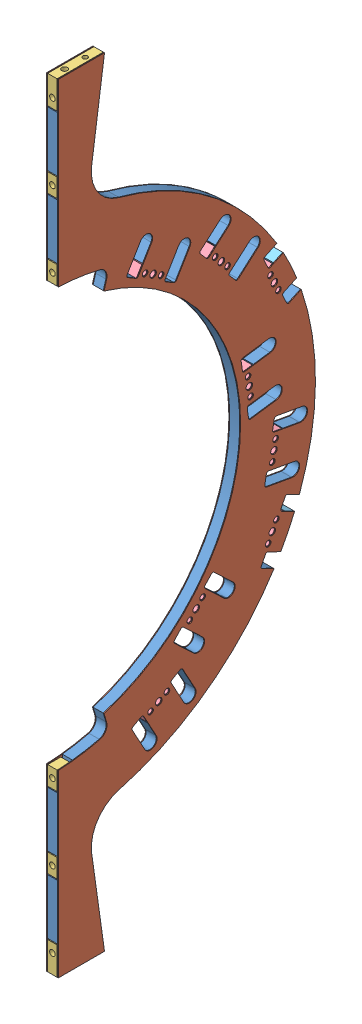
SolidWorks assembly Barrel 3 support panel assy, configuration Right. Lengths in mm.
Overall size (6.75 416 137.5).
28 component instances, 6 part files, 45 mates.
Components (placement in the parent):
- Barrel 3 support core-1: Barrel 3 support core [right] x (0 0 -1) z (1 0 0)
- Barrel 3 support skin-1: Barrel 3 support skin [barrel 3 right skin 1] at (2.92 0 0) x (0 0 -1) z (1 0 0) size (137.5 416 0.41)
- Barrel 3 support skin-2: Barrel 3 support skin [barrel 3 right skin 2] at (-2.92 0 0) x (0 0 -1) z (1 0 0)
- Barrel 1 support inserts-1: Barrel 1 support inserts [insert 1] x (0 0 -1) z (1 0 0) size (24.73 15 5.03)
- Barrel 1 support inserts-2: Barrel 1 support inserts [insert 1] x (0 0 -1) z (-1 0 0) size (24.73 15 5.03)
- Barrel 1 support inserts-3: Barrel 1 support inserts [insert 2] at (0 -3.5 0) x (0 0 -1) z (1 0 0) size (7.5 10 5.03)
- Barrel 1 support inserts-4: Barrel 1 support inserts [insert 2] at (0 44 0) x (0 0 -1) z (-1 0 0) size (7.5 10 5.03)
- Barrel 1 support inserts-5: Barrel 1 support inserts [insert 2] at (0 -44 0) x (0 0 -1) z (1 0 0) size (7.5 10 5.03)
- Barrel 1 support inserts-6: Barrel 1 support inserts [insert 2] at (0 3.5 0) x (0 0 -1) z (-1 0 0) size (7.5 10 5.03)
- Adhesive-1: Adhesive [Default] at origin
- Barrel 3-4 support panel ladder mounting block-1: Barrel 3-4 support panel ladder mounting block [Default for barrel 4 support panel] at (-0.505 92.4422 -55.2185) x (0 -0.858503 0.512809) z (0 0.512809 0.858503)
- Barrel 3-4 support panel ladder mounting block-18: Barrel 3-4 support panel ladder mounting block [Default for barrel 4 support panel] at (-0.505 80.0329 -91.7246) x (0 -0.657452 0.753497) z (0 0.753497 0.657452)
- Barrel 3-4 support panel ladder mounting block-24: Barrel 3-4 support panel ladder mounting block [Default for barrel 4 support panel] at (-0.505 56.1248 -120.0908) x (0 -0.423396 0.905945) z (0 0.905945 0.423396)
- Barrel 3-4 support panel ladder mounting block-19: Barrel 3-4 support panel ladder mounting block [Default for barrel 4 support panel] at (-0.505 -21.4676 -119.8241) x (0 0.176352 0.984327) z (0 0.984327 -0.176352)
- Barrel 3-4 support panel ladder mounting block-20: Barrel 3-4 support panel ladder mounting block [Default for barrel 4 support panel] at (-0.505 -106.8994 -58.2339) x (0 0.878154 0.478378) z (0 0.478378 -0.878154)
- Barrel 3-4 support panel ladder mounting block-13: Barrel 3-4 support panel ladder mounting block [Default for barrel 4 support panel] at (-0.505 14.7732 -106.6602) x (0 -0.137198 0.990544) z (0 0.990544 0.137198)
- Barrel 3-4 support panel ladder mounting block-14: Barrel 3-4 support panel ladder mounting block [Default for barrel 4 support panel] at (-0.505 -73.9537 -78.2656) x (0 0.686801 0.726845) z (0 0.726845 -0.686801)
- Barrel 3-4 support panel ladder mounting block-25: Barrel 3-4 support panel ladder mounting block [Default for barrel 4 support panel] at (-0.505 -58.5544 -118.925) x (0 0.441725 0.897151) z (0 0.897151 -0.441725)
- Barrel 3-4 support panel ladder mounting block-28: Barrel 3-4 support panel ladder mounting block [Default for barrel 4 support panel] at (0.505 92.4422 -55.2185) x (0 0.858503 -0.512809) z (0 0.512809 0.858503) (suppressed, hidden)
- Barrel 3-4 support panel ladder mounting block-34: Barrel 3-4 support panel ladder mounting block [Default for barrel 4 support panel] at (0.505 80.0329 -91.7246) x (0 0.657452 -0.753497) z (0 0.753497 0.657452) (suppressed, hidden)
- Barrel 3-4 support panel ladder mounting block-40: Barrel 3-4 support panel ladder mounting block [Default for barrel 4 support panel] at (0.505 56.1248 -120.0908) x (0 0.423396 -0.905945) z (0 0.905945 0.423396) (suppressed, hidden)
- Barrel 3-4 support panel ladder mounting block-35: Barrel 3-4 support panel ladder mounting block [Default for barrel 4 support panel] at (0.505 -21.4676 -119.8241) x (0 -0.176352 -0.984327) z (0 0.984327 -0.176352) (suppressed, hidden)
- Barrel 3-4 support panel ladder mounting block-36: Barrel 3-4 support panel ladder mounting block [Default for barrel 4 support panel] at (0.505 -106.8994 -58.2339) x (0 -0.878154 -0.478378) z (0 0.478378 -0.878154) (suppressed, hidden)
- Barrel 3-4 support panel ladder mounting block-29: Barrel 3-4 support panel ladder mounting block [Default for barrel 4 support panel] at (0.505 14.7732 -106.6602) x (0 0.137198 -0.990544) z (0 0.990544 0.137198) (suppressed, hidden)
- Barrel 3-4 support panel ladder mounting block-30: Barrel 3-4 support panel ladder mounting block [Default for barrel 4 support panel] at (0.505 -73.9537 -78.2656) x (0 -0.686801 -0.726845) z (0 0.726845 -0.686801) (suppressed, hidden)
- Barrel 3-4 support panel ladder mounting block-41: Barrel 3-4 support panel ladder mounting block [Default for barrel 4 support panel] at (0.505 -58.5544 -118.925) x (0 -0.441725 -0.897151) z (0 0.897151 -0.441725) (suppressed, hidden)
- Barrel 3 support core plug 1-1: Barrel 3 support core plug 1 [right] x (0 0.423396 -0.905945) z (1 0 0)
- Barrel 3 support core plug 1-2: Barrel 3 support core plug 1 [right] x (0 -0.441725 -0.897151) z (1 0 0)
Mates (geometry in assembly coordinates):
- Coincident1: coincident anti-aligned: plane of Barrel 3 support core-1 through (0 0 0) normal (0 0 -1); plane of assembly through (0 0 0) normal (0 0 1)
- Coincident2: coincident aligned: plane of Barrel 3 support core-1 through (0 0 0) normal (1 0 0); plane of assembly through (0 0 0) normal (1 0 0)
- Coincident3: coincident aligned: plane of Barrel 3 support core-1; plane of assembly through (0 0 0) normal (0 1 0)
- Coincident4: coincident aligned: plane of Barrel 1 support inserts-1 through (0 0 0) normal (1 0 0); plane of assembly through (0 0 0) normal (1 0 0)
- Coincident5: coincident anti-aligned: plane of Barrel 1 support inserts-1 through (0 0 0) normal (0 0 -1); plane of assembly through (0 0 0) normal (0 0 1)
- Coincident6: coincident aligned: plane of Barrel 1 support inserts-1; plane of assembly through (0 0 0) normal (0 1 0)
- Coincident7: coincident anti-aligned: plane of Barrel 1 support inserts-2; plane of assembly through (0 0 0) normal (0 1 0)
- Coincident8: coincident anti-aligned: plane of Barrel 1 support inserts-2; plane of assembly through (0 0 0) normal (0 0 1)
- Coincident9: coincident anti-aligned: plane of Barrel 1 support inserts-2 through (0 0 0) normal (-1 0 0); plane of assembly through (0 0 0) normal (1 0 0)
- Coincident10: coincident aligned: plane of Barrel 1 support inserts-3 through (0 -3.5 0) normal (1 0 0); plane of assembly through (0 0 0) normal (1 0 0)
- Coincident11: coincident anti-aligned: plane of Barrel 1 support inserts-3 through (0 -3.5 0) normal (0 0 -1); plane of assembly through (0 0 0) normal (0 0 1)
- Coincident13: coincident anti-aligned: plane of Barrel 1 support inserts-4 through (0 44 0) normal (-1 0 0); plane of assembly through (0 0 0) normal (1 0 0)
- Coincident14: coincident anti-aligned: plane of Barrel 1 support inserts-4; plane of assembly through (0 0 0) normal (0 0 1)
- Coincident18: coincident anti-aligned: plane of Barrel 3 support skin-1 through (2.92 0 0) normal (0 0 -1); plane of assembly through (0 0 0) normal (0 0 1)
- Coincident19: coincident aligned: plane of Barrel 3 support skin-1; plane of assembly through (0 0 0) normal (0 1 0)
- Coincident20: coincident aligned: plane of Barrel 3 support skin-2; plane of assembly through (0 0 0) normal (0 1 0)
- Coincident21: coincident anti-aligned: plane of Barrel 3 support skin-2 through (-2.92 0 0) normal (0 0 -1); plane of assembly through (0 0 0) normal (0 0 1)
- Coincident22: coincident anti-aligned: plane of Barrel 3 support core-1 through (2.715 156.4127 -42.1789) normal (1 0 0); plane of Barrel 3 support skin-1 through (2.715 156.4127 -42.1789) normal (-1 0 0)
- Coincident23: coincident anti-aligned: plane of Barrel 3 support core-1 through (-2.715 156.4127 -42.1789) normal (-1 0 0); plane of Barrel 3 support skin-2 through (-2.715 156.4127 -42.1789) normal (1 0 0)
- Distance1: distance = 3.5 mm aligned: plane of Barrel 1 support inserts-3; plane of assembly through (0 0 0) normal (0 1 0)
- Distance2: distance = 44 mm anti-aligned: plane of Barrel 1 support inserts-4; plane of assembly through (0 0 0) normal (0 1 0)
- Distance25: distance = 0.1 mm anti-aligned: plane of Barrel 3-4 support panel ladder mounting block-1 through (2.615 97.7849 -50.2561) normal (1 0 0); plane of Barrel 3 support skin-1 through (2.715 156.4127 -42.1789) normal (-1 0 0)
- Distance26: distance = 0.1 mm anti-aligned: plane of Barrel 3-4 support panel ladder mounting block-18 through (2.615 86.6499 -88.6611) normal (1 0 0); plane of Barrel 3 support skin-1 through (2.715 156.4127 -42.1789) normal (-1 0 0)
- Distance27: distance = 0.1 mm anti-aligned: plane of Barrel 3-4 support panel ladder mounting block-24 through (2.615 63.331 -118.9769) normal (1 0 0); plane of Barrel 3 support skin-1 through (2.715 156.4127 -42.1789) normal (-1 0 0)
- Distance3: distance = 0.25 mm anti-aligned: plane of Barrel 3-4 support panel ladder mounting block-1 through (-3.625 97.7849 -50.2561) normal (0 0.858503 -0.512809); plane of Barrel 3 support skin-2 through (-3.125 90.9484 -62.1887) normal (0 -0.858503 0.512809)
- Distance5: distance = 0.25 mm anti-aligned: plane of Barrel 3-4 support panel ladder mounting block-18 through (-3.625 86.6499 -88.6611) normal (0 0.657452 -0.753497); plane of Barrel 3 support skin-2 through (-3.125 86.6259 -89.0138) normal (0 -0.657452 0.753497)
- Distance7: distance = 0.25 mm anti-aligned: plane of Barrel 3-4 support panel ladder mounting block-24 through (-3.625 63.331 -118.9769) normal (0 0.423396 -0.905945); plane of Barrel 3 support skin-2 through (-3.125 63.2103 -119.3093) normal (0 -0.423396 0.905945)
- Distance10: distance = 0.25 mm anti-aligned: plane of Barrel 3-4 support panel ladder mounting block-24 through (-3.625 61.6018 -115.2771) normal (0 0.905945 0.423396); plane of Barrel 3 support skin-2 through (-3.125 63.4516 -118.6446) normal (0 -0.905945 -0.423396)
- Distance12: distance = 0.25 mm anti-aligned: plane of Barrel 3-4 support panel ladder mounting block-18 through (-3.625 83.9648 -85.5838) normal (0 0.753497 0.657452); plane of Barrel 3 support skin-2 through (-3.125 84.3176 -85.6078) normal (0 -0.753497 -0.657452)
- Distance14: distance = 0.25 mm anti-aligned: plane of Barrel 3-4 support panel ladder mounting block-1 through (-3.625 94.2788 -48.1618) normal (0 0.512809 0.858503); plane of Barrel 3 support skin-2 through (-3.125 94.6216 -48.0754) normal (0 -0.512809 -0.858503)
- Distance30: distance = 0.1 mm anti-aligned: plane of Barrel 3-4 support panel ladder mounting block-28 through (-3.225 85.486 -62.306) normal (1 0 0); plane of Barrel 3 support skin-2 through (-2.715 156.4127 -42.1789) normal (1 0 0)
- Distance29: distance = 0.1 mm anti-aligned: plane of Barrel 3-4 support panel ladder mounting block-34 through (-3.225 70.3366 -94.5466) normal (1 0 0); plane of Barrel 3 support skin-2 through (-2.715 156.4127 -42.1789) normal (1 0 0)
- Distance28: distance = 0.1 mm anti-aligned: plane of Barrel 3-4 support panel ladder mounting block-40 through (-3.225 46.7747 -121.0978) normal (1 0 0); plane of Barrel 3 support skin-2 through (-2.715 156.4127 -42.1789) normal (1 0 0)
- Distance15: distance = 0.25 mm anti-aligned: plane of ? through (-2.8182 100.1543 -37.8675) normal (0 0.850362 -0.526199); plane of Barrel 3 support skin-1 through (2.715 90.9484 -62.1887) normal (0 -0.858503 0.512809)
- Distance17: distance = 0.25 mm anti-aligned: plane of ? through (3.3558 94.4143 -34.3156) normal (0 0.526199 0.850362); plane of Barrel 3 support skin-1 through (2.715 95.1649 -46.9907) normal (0 -0.502963 -0.864308)
- Distance19: distance = 0.25 mm anti-aligned: plane of ? through (-2.8182 91.7443 -75.7289) normal (0 0.649973 -0.759957); plane of Barrel 3 support skin-1 through (2.715 86.4138 -86.9566) normal (0 -0.664765 0.747053)
- Distance20: distance = 0.25 mm anti-aligned: plane of ?; plane of Barrel 3 support skin-1 through (2.715 84.0724 -83.5733) normal (0 -0.747053 -0.664765)
- Distance23: distance = 0.25 mm anti-aligned: plane of ? through (-2.8182 72.516 -108.8591) normal (0 0.417113 -0.908855); plane of Barrel 3 support skin-1 through (2.715 63.8448 -118.9709) normal (0 -0.428215 0.903677)
- Distance24: distance = 0.25 mm anti-aligned: plane of ?; plane of Barrel 3 support skin-1 through (2.715 64.0826 -118.305) normal (0 -0.903677 -0.428215)
- Coincident48: coincident aligned: line of Barrel 3 support core-1 through (-47.6229 0 0) axis (1 0 0); line of Barrel 3 support core plug 1-1 through (-47.6229 0 0) axis (1 0 0)
- Coincident49: coincident aligned: plane of Barrel 3 support core-1 through (0 0 0) normal (1 0 0); plane of Barrel 3 support core plug 1-1 through (0 0 0) normal (1 0 0)
- Parallel1: parallel aligned: plane of Barrel 3-4 support panel ladder mounting block-24 through (-0.505 56.1248 -120.0908) normal (0 0.905945 0.423396); plane of Barrel 3 support core plug 1-1
- Coincident51: coincident aligned: line of Barrel 3 support core-1 through (-47.6229 0 0) axis (1 0 0); line of Barrel 3 support core plug 1-2 through (-47.6229 0 0) axis (1 0 0)
- Coincident52: coincident aligned: plane of Barrel 3 support core-1 through (0 0 0) normal (1 0 0); plane of Barrel 3 support core plug 1-2 through (0 0 0) normal (1 0 0)
- Parallel2: parallel aligned: plane of Barrel 3-4 support panel ladder mounting block-25 through (-0.505 -58.5544 -118.925) normal (0 0.897151 -0.441725); unknown of Barrel 3 support core plug 1-2
